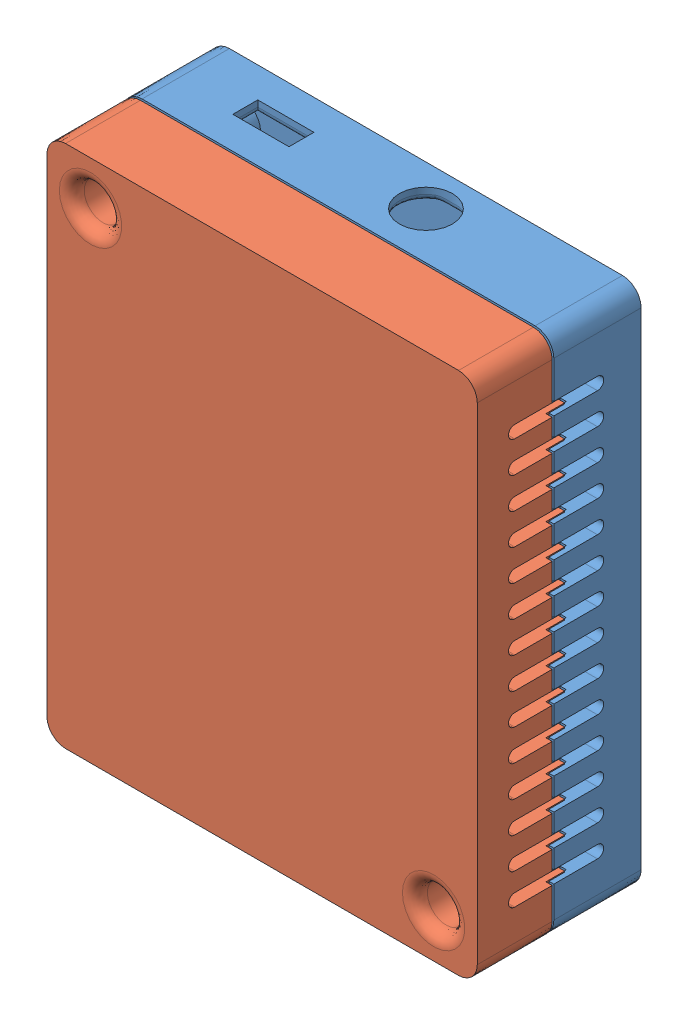
SolidWorks assembly Assem1, configuration Default. Lengths in mm.
Overall size (69.21 84.16 29.48).
2 component instances, 2 part files, 0 mates.
Components (placement in the parent):
- base-1: base [Default] at (30.8795 40.5413 66.9663) size (69 84 17)
- top-1: top [Default] at (31.0941 40.7047 89.4501) x (1 0 0) z (0 0 -1) size (69 84 15)
